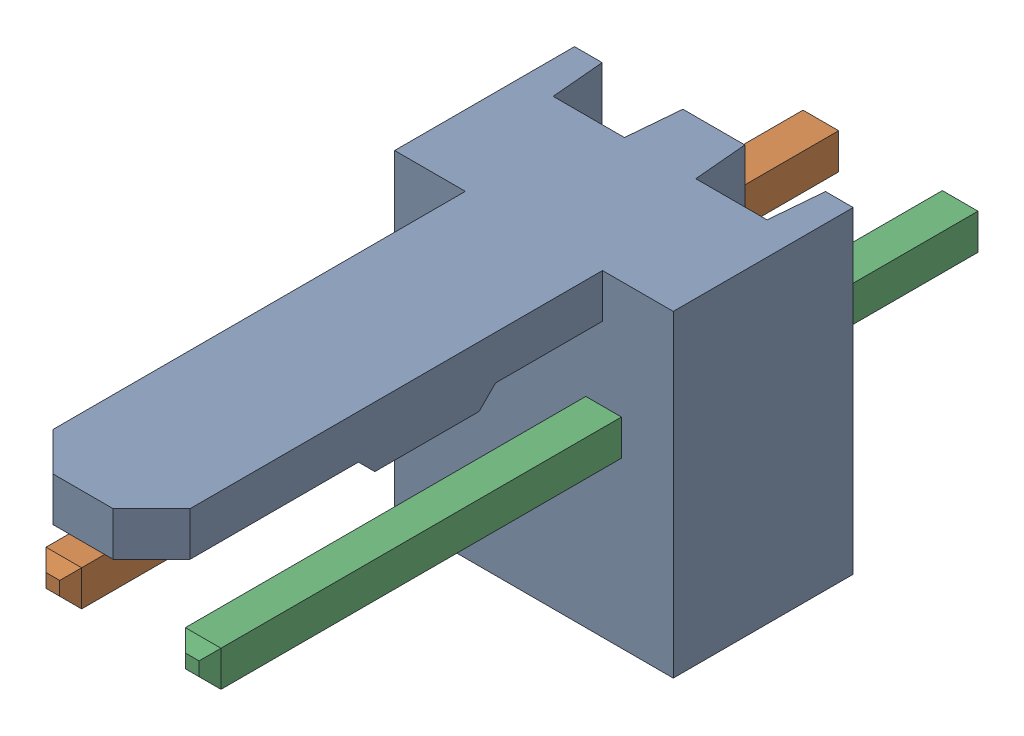
SolidWorks assembly Molex PCB 2 pin v2_2, configuration Predeterminado. Lengths in mm.
Overall size (5.08 5.79 14.92).
3 component instances, 2 part files, 0 mates.
Components (placement in the parent):
- BASE9710016_1-1: BASE9710016_1 [Predeterminado] at (2.54 2.895 -8.22) size (5.08 5.79 11.5)
- PINO9710016_1-1: PINO9710016_1 [Predeterminado] at (1.27 3.325 -0.72) size (0.65 0.65 14.2)
- PINO9710016_1-2: PINO9710016_1 [Predeterminado] at (3.81 3.325 -0.72) size (0.65 0.65 14.2)
